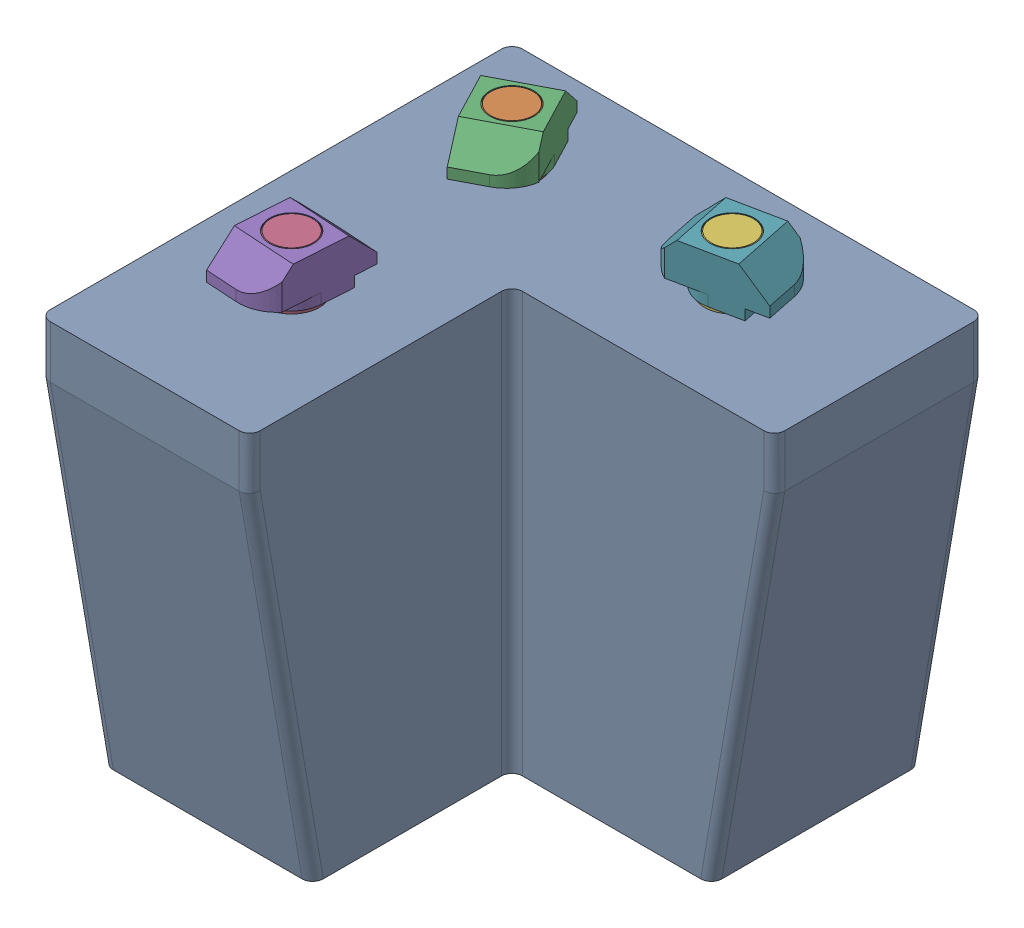
SolidWorks assembly front_left_foot, configuration Default. Lengths in mm.
Overall size (45 45 45).
7 component instances, 3 part files, 0 mates.
Components (placement in the parent):
- budget_foot_Front Right Foot-1: budget_foot_Front Right Foot [Default] at (28.3115 276.9149 684.384) x (0 0 1) z (-1 0 0) size (45 40 45)
- m5_low_profile_screw_template_M5 x 10-1: m5_low_profile_screw_template_M5 x 10 [Default] at (38.3115 281.9149 694.384) x (0 1 0) z (-0.452256 0 0.891888) size (11.62 9 9)
- m5_locking_t_nut_20x20_generic-1: m5_locking_t_nut_20x20_generic [Default] at (40.9722 281.9149 692.9982) x (-0.461938 0 -0.886912) z (-0.886912 0 0.461938) size (10 4.5 6)
- m5_low_profile_screw_template_M5 x 10-2: m5_low_profile_screw_template_M5 x 10 [Default] at (38.3115 281.9149 715.384) x (0 1 0) z (-0.452256 0 0.891888) size (11.62 9 9)
- m5_locking_t_nut_20x20_generic-2: m5_locking_t_nut_20x20_generic [Default] at (41.3055 281.9149 715.5732) x (0.063081 0 -0.998008) z (-0.998008 0 -0.063081) size (10 4.5 6)
- m5_low_profile_screw_template_M5 x 10-3: m5_low_profile_screw_template_M5 x 10 [Default] at (59.3115 281.9149 694.384) x (0 1 0) z (-0.452256 0 0.891888) size (11.62 9 9)
- m5_locking_t_nut_20x20_generic-3: m5_locking_t_nut_20x20_generic [Default] at (58.7073 281.9149 691.4454) x (-0.979508 0 0.201404) z (0.201404 0 0.979508) size (10 4.5 6)
